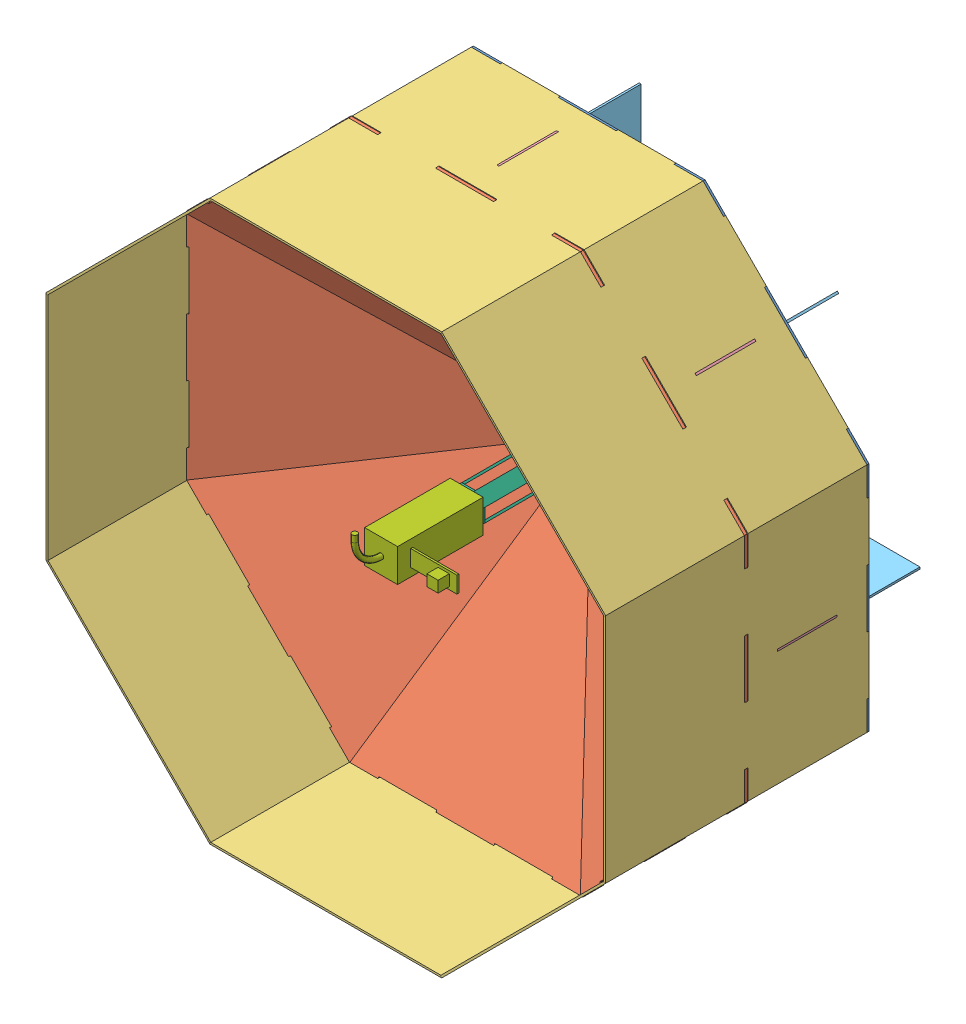
SolidWorks assembly Montagem1, configuration Valor predeterminado. Lengths in mm.
Overall size (851.28 851.28 477.5).
35 component instances, 7 part files, 17 mates.
Components (placement in the parent):
- base certa-1: base certa [Valor predeterminado] at (79.1914 -19.7979 845) size (850 850 3)
- parede-1: parede [Valor predeterminado] at (54.1914 -19.7979 848) x (0 1 0) z (0.414388 0 0.9101) size (352.08 440.22 4)
- paredinha-1: paredinha [Valor predeterminado] at (-345.8086 156.2437 848) x (0 1 0) z (1 0 0) size (352.08 400 3)
- suporte interno-1: suporte interno [Valor predeterminado] at (-342.8086 -18.2971 848) x (1 0 0) z (0 -1 0) size (400 183.76 3)
- pés-1: pés [Valor predeterminado] at (-345.8086 -18.2979 767.5) x (1 0 0) z (0 -1 0) size (300 80.5 3)
- base da estrutura-1: base da estrutura [Valor predeterminado] at (79.1914 -19.7979 848) x (1 0 0) z (0 -1 0) size (50 183 50)
- parede-9: parede [Valor predeterminado] at (61.5138 -37.4755 848) x (-0.707107 0.707107 0) z (0.293016 0.293016 0.9101) size (352.08 440.22 4)
- parede-10: parede [Valor predeterminado] at (79.1914 -44.7979 848) x (-1 0 0) z (0 0.414388 0.9101) size (352.08 440.22 4)
- parede-11: parede [Valor predeterminado] at (96.8691 -37.4755 848) x (-0.707107 -0.707107 0) z (-0.293016 0.293016 0.9101) size (352.08 440.22 4)
- parede-12: parede [Valor predeterminado] at (104.1914 -19.7979 848) x (0 -1 0) z (-0.414388 0 0.9101) size (352.08 440.22 4)
- parede-13: parede [Valor predeterminado] at (96.8691 -2.1202 848) x (0.707107 -0.707107 0) z (-0.293016 -0.293016 0.9101) size (352.08 440.22 4)
- parede-14: parede [Valor predeterminado] at (79.1914 5.2021 848) x (1 0 0) z (0 -0.414388 0.9101) size (352.08 440.22 4)
- parede-15: parede [Valor predeterminado] at (61.5138 -2.1202 848) x (0.707107 0.707107 0) z (0.293016 -0.293016 0.9101) size (352.08 440.22 4)
- suporte interno-10: suporte interno [Valor predeterminado] at (-220.2688 -317.1357 848) x (0.707107 0.707107 0) z (0.707107 -0.707107 0) size (400 183.76 3)
- suporte interno-11: suporte interno [Valor predeterminado] at (77.6907 -441.7979 848) x (0 1 0) z (1 0 0) size (400 183.76 3)
- suporte interno-12: suporte interno [Valor predeterminado] at (376.5293 -319.2581 848) x (-0.707107 0.707107 0) z (0.707107 0.707107 0) size (400 183.76 3)
- suporte interno-13: suporte interno [Valor predeterminado] at (501.1914 -21.2986 848) x (-1 0 0) z (0 1 0) size (400 183.76 3)
- suporte interno-14: suporte interno [Valor predeterminado] at (378.6517 277.54 848) x (-0.707107 -0.707107 0) z (-0.707107 0.707107 0) size (400 183.76 3)
- suporte interno-15: suporte interno [Valor predeterminado] at (80.6922 402.2021 848) x (0 -1 0) z (-1 0 0) size (400 183.76 3)
- suporte interno-16: suporte interno [Valor predeterminado] at (-218.1464 279.6624 848) x (0.707107 -0.707107 0) z (-0.707107 -0.707107 0) size (400 183.76 3)
- paredinha-9: paredinha [Valor predeterminado] at (-345.8091 -195.8381 848) x (-0.707107 0.707107 0) z (0.707107 0.707107 0) size (352.08 400 3)
- paredinha-10: paredinha [Valor predeterminado] at (-96.8501 -444.7979 848) x (-1 0 0) z (0 1 0) size (352.08 400 3)
- paredinha-11: paredinha [Valor predeterminado] at (255.2317 -444.7984 848) x (-0.707107 -0.707107 0) z (-0.707107 0.707107 0) size (352.08 400 3)
- paredinha-12: paredinha [Valor predeterminado] at (504.1914 -195.8394 848) x (0 -1 0) z (-1 0 0) size (352.08 400 3)
- paredinha-13: paredinha [Valor predeterminado] at (504.192 156.2424 848) x (0.707107 -0.707107 0) z (-0.707107 -0.707107 0) size (352.08 400 3)
- paredinha-14: paredinha [Valor predeterminado] at (255.233 405.2021 848) x (1 0 0) z (0 -1 0) size (352.08 400 3)
- paredinha-15: paredinha [Valor predeterminado] at (-96.8488 405.2027 848) x (0.707107 0.707107 0) z (0.707107 -0.707107 0) size (352.08 400 3)
- pés-9: pés [Valor predeterminado] at (-222.3896 -319.2576 767.5) x (0.707107 0.707107 0) z (0.707107 -0.707107 0) size (300 80.5 3)
- pés-10: pés [Valor predeterminado] at (77.6914 -444.7979 767.5) x (0 1 0) z (1 0 0) size (300 80.5 3)
- pés-11: pés [Valor predeterminado] at (378.6512 -321.3789 767.5) x (-0.707107 0.707107 0) z (0.707107 0.707107 0) size (300 80.5 3)
- pés-12: pés [Valor predeterminado] at (504.1914 -21.2979 767.5) x (-1 0 0) z (0 1 0) size (300 80.5 3)
- pés-13: pés [Valor predeterminado] at (380.7725 279.6619 767.5) x (-0.707107 -0.707107 0) z (-0.707107 0.707107 0) size (300 80.5 3)
- pés-14: pés [Valor predeterminado] at (80.6914 405.2021 767.5) x (0 -1 0) z (-1 0 0) size (300 80.5 3)
- pés-15: pés [Valor predeterminado] at (-220.2683 281.7832 767.5) x (0.707107 -0.707107 0) z (-0.707107 -0.707107 0) size (300 80.5 3)
- bombeiro-2: bombeiro [Valor predeterminado] at (79.1914 -19.7979 1031) x (1 0 0) z (0 -1 0) size (120 174 75)
Mates (geometry in assembly coordinates):
- Coincidente7: coincident anti-aligned: line of base certa-1 through (54.1914 -19.7979 848) axis (0 -1 0); line of parede-1 through (54.1914 -30.1532 848) axis (0 1 0)
- Coincidente8: coincident: point of base certa-1; point of parede-1
- Coincidente9: coincident anti-aligned: plane of base certa-1 through (-342.8086 112.2327 848) normal (-1 0 0); plane of paredinha-1 through (-342.8086 156.2437 848) normal (1 0 0)
- Coincidente10: coincident anti-aligned: line of base certa-1 through (-342.8086 -63.808 845) axis (0 -1 0); line of paredinha-1 through (-342.8086 -151.8277 845) axis (0 1 0)
- Coincidente12: coincident anti-aligned: line of base certa-1 through (-345.8086 112.2327 848) axis (0 0 -1); line of paredinha-1 through (-345.8086 112.2327 845) axis (0 0 1)
- Coincidente13: coincident aligned: line of parede-1 through (-342.8086 112.2323 1028.7624) axis (0 -1 0); line of paredinha-1 through (-342.8086 156.2437 1028.7624) axis (0 -1 0)
- Coincidente14: coincident anti-aligned: plane of base certa-1 through (79.1914 -19.7979 848) normal (0 0 1); plane of suporte interno-1 through (-231.5229 -21.2971 848) normal (0 0 -1)
- Coincidente15: coincident aligned: line of paredinha-1 through (-345.8086 -21.2971 983.5718) axis (0 0 -1); line of suporte interno-1 through (-345.8086 -21.2971 983.5718) axis (0 0 -1)
- Coincidente16: coincident anti-aligned: line of base certa-1 through (-345.8086 24.2123 845) axis (0 -1 0); line of pés-1 through (-345.8086 -21.2979 845) axis (0 1 0)
- Coincidente17: coincident aligned: line of suporte interno-1 through (-60.0943 -21.2971 848) axis (0 1 0); line of pés-1 through (-60.0943 -21.2979 848) axis (0 1 0)
- Coincidente18: coincident: line of base certa-1 through (-2.9514 -18.2979 845) axis (-1 0 0); plane of pés-1 through (-345.8086 -18.2979 767.5) normal (0 1 0)
- Coincidente19: coincident anti-aligned: plane of base certa-1 through (79.1914 -19.7979 848) normal (0 0 1); plane of base da estrutura-1 through (79.1914 -19.7979 848) normal (0 0 -1)
- Coincidente25: coincident aligned: line of base certa-1 through (54.1914 -30.1532 848) axis (0.707107 -0.707107 0); line of base da estrutura-1 through (54.1914 -30.1532 848) axis (0.707107 -0.707107 0)
- Coincidente26: coincident aligned: line of base certa-1 through (89.5468 -44.7979 848) axis (0.707107 0.707107 0); line of base da estrutura-1 through (89.5468 -44.7979 848) axis (0.707107 0.707107 0)
- Coincidente27: coincident aligned: line of base da estrutura-1 through (89.5468 5.2021 1031) axis (-1 0 0); line of bombeiro-2 through (104.1914 5.2021 1031) axis (-1 0 0)
- Coincidente28: coincident anti-aligned: plane of base da estrutura-1 through (79.1914 -19.7979 1031) normal (0 0 1); plane of bombeiro-2 through (79.1914 -19.7979 1031) normal (0 0 -1)
- Coincidente29: coincident aligned: line of base da estrutura-1 through (54.1914 -9.4425 1031) axis (0 -1 0); line of bombeiro-2 through (54.1914 5.2021 1031) axis (0 -1 0)
